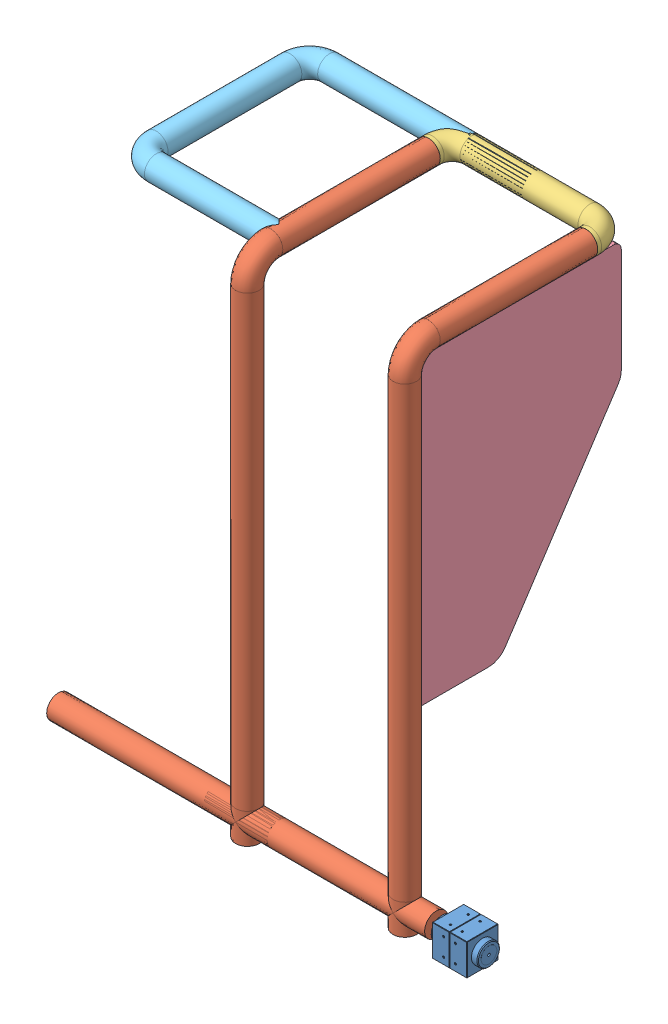
SolidWorks assembly half_seat, configuration Default. Lengths in mm.
Overall size (546.87 653.61 325.22).
6 component instances, 5 part files, 8 mates.
Components (placement in the parent):
- LINOS-FI-1030-35C_bulk-1: LINOS-FI-1030-35C_bulk [Default] at (36.7653 23.6083 41.7735) size (60.2 40 40)
- Part10^half_seat-1: Part10^half_seat [Default] at origin size (280 653.61 245) (virtual)
- Part11^half_seat-1: Part11^half_seat [Default] at (0 200 20) size (230 30 45) (virtual)
- Part10^half_seat-2: Part10^half_seat [Default] at (-200 0 0) size (280 653.61 245) (virtual)
- Part12^half_seat-1: Part12^half_seat [Default] at (-5 200 0) size (24 385 320.22) (virtual)
- Part13^half_seat-1: Part13^half_seat [Default] at (-0.8022 200 20) size (300 30 250) (virtual)
Mates (geometry in assembly coordinates):
- Coincident4: coincident aligned: circle of Part10^Assem2-1; circle of Part11^Assem2-1
- Coincident5: coincident anti-aligned: circle of Part11^Assem2-1; circle of Part10^Assem2-2
- Coincident6: coincident aligned: plane of Part10^half_seat-1 through (-40 0 41.7735) normal (0 -1 0); plane of Part10^half_seat-2 through (-240 0 41.7735) normal (0 -1 0)
- Concentric1: concentric anti-aligned: cylinder of Part11^half_seat-1 through (-65 638.6083 -218.2265) axis (-1 0 0) radius 15; cylinder of Part13^half_seat-1 through (-385.8022 638.6083 -218.2265) axis (1 0 0) radius 15
- Parallel1: parallel anti-aligned: cylinder of Part10^half_seat-2 through (-240 638.6083 11.7735) axis (0 0 -1) radius 15; cylinder of Part13^half_seat-1 through (-420.8022 638.6083 -193.2265) axis (0 0 1) radius 15
- Tangent1: tangent anti-aligned: cylinder of Part10^half_seat-1 through (-40 638.6083 11.7735) axis (0 0 -1) radius 15; plane of Part12^half_seat-1 through (-35 623.6083 11.7735) normal (0 1 0)
- Tangent2: tangent anti-aligned: cylinder of Part10^half_seat-1 through (-40 38.6083 41.7735) axis (0 1 0) radius 15; plane of Part12^half_seat-1 through (-35 238.6083 26.7735) normal (0 0 1)
- Coincident9: coincident anti-aligned: plane of Part12^half_seat-1 through (-45 608.6083 11.7735) normal (-1 0 0)
